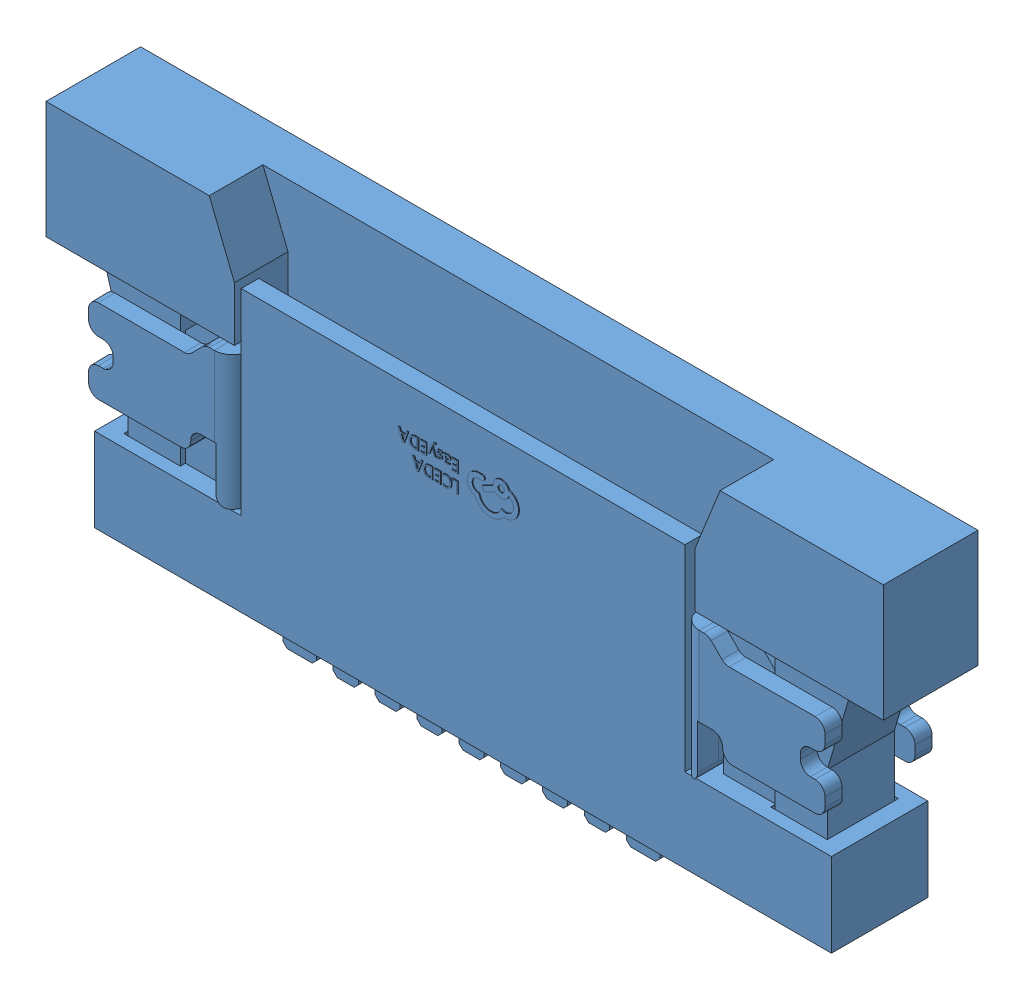
SolidWorks assembly FPC-SMD-8P-型号2, configuration 默认. Lengths in mm.
Overall size (10 5 1.28).
4 component instances, 1 part files, 0 mates.
Components (placement in the parent):
- FPC-SMD-8P-型号2(2)^FPC-SMD-8P-型号2-1: FPC-SMD-8P-型号2(2)^FPC-SMD-8P-型号2 [默认] at origin size (10 5 1.28) (virtual)
  - FPC2^FPC-SMD-8P-型号2(2)_FPC-SMD-8P-型号2-1: FPC2^FPC-SMD-8P-型号2(2)_FPC-SMD-8P-型号2 [默认] at (-12.446 -9.017 1.6001) size (10 5 1.28) (virtual)
    - FPC-SMD_8P-P0.50_HDGC_0.5K-1.2S-8PWB^FPC2_FPC-SMD-8P-型号2(2)_FPC-SMD-8P-型号2-1: FPC-SMD_8P-P0.50_HDGC_0.5K-1.2S-8PWB^FPC2_FPC-SMD-8P-型号2(2)_FPC-SMD-8P-型号2 [默认] at origin size (10 5 1.28) (virtual)
      - COMPOUND^FPC-SMD_8P-P0.50_HDGC_0.5K-1.2S-8PWB_FPC2_FPC-SMD-8P-型号2(2)_FPC-SMD-8P-型号2-1: COMPOUND^FPC-SMD_8P-P0.50_HDGC_0.5K-1.2S-8PWB_FPC2_FPC-SMD-8P-型号2(2)_FPC-SMD-8P-型号2 [默认] at origin size (10 5 1.28) (virtual)
